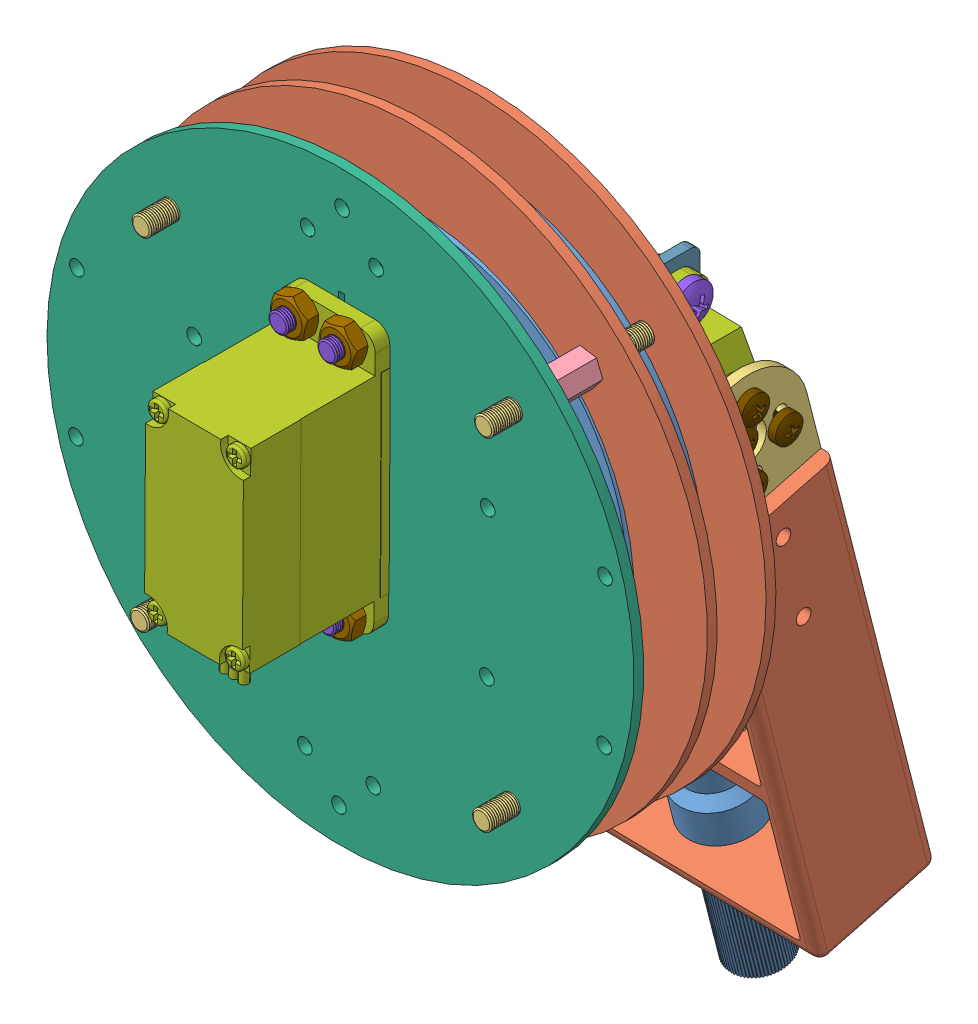
SolidWorks assembly 二自由度云台, configuration 默认. Lengths in mm.
55 component instances, 21 part files, 7 mates.
Components (placement in the parent):
- ______-1: ______ [默认] at (-82.3589 -57.7244 90.6612) x (1 0 0) z (0 -1 0) size (95 10 95)
- ____-1: ____ [默认] at (-82.3589 -57.7244 78.6612) x (0 0 1) z (-0.711112 -0.703078 0) size (2 120 120)
- ____-2: ____ [默认] at (-82.3589 -57.7244 92.6612) x (0 0 -1) z (0.711112 0.703078 0) size (2 120 120)
- cross recessed pan head screws gb_GB_CROSS_SCREWS_TYPE1 M4X35-35  H type-S-1: cross recessed pan head screws gb_GB_CROSS_SCREWS_TYPE1 M4X35-35  H type-S [默认] at (-47.5565 -92.9245 75.5612) x (0 0 1) z (-1 0 0) size (38.1 8.13 8.3)
- cross recessed pan head screws gb_GB_CROSS_SCREWS_TYPE1 M4X35-35  H type-S-2: cross recessed pan head screws gb_GB_CROSS_SCREWS_TYPE1 M4X35-35  H type-S [默认] at (-117.559 -92.5268 75.5612) x (0 0 1) z (-0.986603 0.163137 0) size (38.1 8.13 8.3)
- cross recessed pan head screws gb_GB_CROSS_SCREWS_TYPE1 M4X35-35  H type-S-3: cross recessed pan head screws gb_GB_CROSS_SCREWS_TYPE1 M4X35-35  H type-S [默认] at (-117.1613 -22.5244 75.5612) x (0 0 1) z (0.908259 -0.418408 0) size (38.1 8.13 8.3)
- cross recessed pan head screws gb_GB_CROSS_SCREWS_TYPE1 M4X35-35  H type-S-4: cross recessed pan head screws gb_GB_CROSS_SCREWS_TYPE1 M4X35-35  H type-S [默认] at (-47.1589 -22.922 75.5612) x (0 0 1) z (-1 0 0) size (38.1 8.13 8.3)
- M4X13________-1: M4X13________ [默认] at (-120.1099 -20.7062 92.6612) x (0.880142 0.47471 0) z (0 0 1) size (6.93 6 13)
- M4X13________-2: M4X13________ [默认] at (-43.7311 -23.4224 92.6612) x (-0.619848 -0.784722 0) z (0 0 1) size (6.93 6 13)
- M4X13________-3: M4X13________ [默认] at (-50.9498 -93.6216 92.6612) x (0.315486 0.94893 0) z (0 0 1) size (6.93 6 13)
- M4X13________-4: M4X13________ [默认] at (-119.242 -89.499 92.6612) x (0.999868 -0.016255 0) z (0 0 1) size (6.93 6 13)
- 001______+____Z-1: 001______+____Z [默认] at (-140.6801 -103.9673 61.1412) size (20.06 19.66 8.9)
- 004 ________-1: 004 ________ [默认] at (-77.1222 -62.0034 226.6612) x (0.999983 -0.005885 0) z (0 0 -1) size (120 120 45.5)
  - ________-1: ________ [默认] at (-6.9598 -21.9991 119) size (120 120 2)
  - ________-1-1: ________-1 [默认] at (4.7275 -13.9483 109) x (0 0 1) z (-1 0 0) size (45.5 56 20)
  - cross recessed pan head screws gb_GB_CROSS_SCREWS_TYPE1 M4X10-10  H type-S-1: cross recessed pan head screws gb_GB_CROSS_SCREWS_TYPE1 M4X10-10  H type-S [默认] at (-10.2725 10.0517 124.1) x (0 0 -1) z (1 0 0) size (13.1 8.13 8.3)
  - cross recessed pan head screws gb_GB_CROSS_SCREWS_TYPE1 M4X10-10  H type-S-2: cross recessed pan head screws gb_GB_CROSS_SCREWS_TYPE1 M4X10-10  H type-S [默认] at (-0.2725 10.0517 124.1) x (0 0 -1) z (-0.157245 -0.98756 0) size (13.1 8.13 8.3)
  - cross recessed pan head screws gb_GB_CROSS_SCREWS_TYPE1 M4X10-10  H type-S-3: cross recessed pan head screws gb_GB_CROSS_SCREWS_TYPE1 M4X10-10  H type-S [默认] at (-10.2725 -38.2483 124.1) x (0 0 -1) z (0.153559 0.988139 0) size (13.1 8.13 8.3)
  - cross recessed pan head screws gb_GB_CROSS_SCREWS_TYPE1 M4X10-10  H type-S-4: cross recessed pan head screws gb_GB_CROSS_SCREWS_TYPE1 M4X10-10  H type-S [默认] at (-0.2725 -38.2483 124.1) x (0 0 -1) z (0.042331 0.999104 0) size (13.1 8.13 8.3)
  - hex nuts, style 1-grades ab gb_GB_FASTENER_NUT_SNAB1 M4-S-1: hex nuts, style 1-grades ab gb_GB_FASTENER_NUT_SNAB1 M4-S [默认] at (-0.2725 10.0517 112.8) x (0.195898 -0.980624 0) z (0 0 -1) size (8.08 7 3.2)
  - hex nuts, style 1-grades ab gb_GB_FASTENER_NUT_SNAB1 M4-S-2: hex nuts, style 1-grades ab gb_GB_FASTENER_NUT_SNAB1 M4-S [默认] at (-10.2725 10.0517 112.8) x (0.923728 0.383049 0) z (0 0 -1) size (8.08 7 3.2)
  - hex nuts, style 1-grades ab gb_GB_FASTENER_NUT_SNAB1 M4-S-3: hex nuts, style 1-grades ab gb_GB_FASTENER_NUT_SNAB1 M4-S [默认] at (-0.2725 -38.2483 112.8) x (-0.289317 0.957233 0) z (0 0 -1) size (8.08 7 3.2)
  - hex nuts, style 1-grades ab gb_GB_FASTENER_NUT_SNAB1 M4-S-4: hex nuts, style 1-grades ab gb_GB_FASTENER_NUT_SNAB1 M4-S [默认] at (-10.2725 -38.2483 112.8) x (0.195898 -0.980624 0) z (0 0 -1) size (8.08 7 3.2)
- 装配体2^二自由度云台-1: 装配体2^二自由度云台 [默认] at (-165.8157 -113.8499 0) x (-0.999814 0.019284 0) z (0 0 1) size (82.4 80 45.14)
  - ________-2-1: ________-2 [默认] at (-64.3589 -68.5794 64.7929) x (0 -0.998863 -0.047683) z (0 -0.047683 0.998863) size (10 4 10)
  - cross recessed pan head screws gb_GB_CROSS_SCREWS_TYPE1 M3X8-8  H type-S-1: cross recessed pan head screws gb_GB_CROSS_SCREWS_TYPE1 M3X8-8  H type-S [默认] at (-61.9589 -68.5794 64.7929) x (-1 0 0) z (0 -0.323721 0.946153) size (10.4 5.69 5.85)
  - hex nuts, style 1-grades ab gb_GB_FASTENER_NUT_SNAB1 M3-S-1: hex nuts, style 1-grades ab gb_GB_FASTENER_NUT_SNAB1 M3-S [默认] at (-99.3589 -82.0794 69.6612) x (0 -0.251604 0.96783) z (-1 0 0) size (6.35 5.5 2.4)
  - ________-1-1: ________-1 [默认] at (-94.3589 -58.0794 54.6612) x (-1 0 0) z (0 0 1) size (45.5 56 20)
  - cross recessed pan head screws gb_GB_CROSS_SCREWS_TYPE1 M4X10-10  H type-S-1: cross recessed pan head screws gb_GB_CROSS_SCREWS_TYPE1 M4X10-10  H type-S [默认] at (-107.4589 -82.0794 69.6612) x (1 0 0) z (0 0.191059 0.981579) size (13.1 8.13 8.3)
  - cross recessed pan head screws gb_GB_CROSS_SCREWS_TYPE1 M4X10-10  H type-S-2: cross recessed pan head screws gb_GB_CROSS_SCREWS_TYPE1 M4X10-10  H type-S [默认] at (-107.4589 -82.0794 59.6612) x (1 0 0) z (0 0.369456 -0.929248) size (13.1 8.13 8.3)
  - hex nuts, style 1-grades ab gb_GB_FASTENER_NUT_SNAB1 M4-S-1: hex nuts, style 1-grades ab gb_GB_FASTENER_NUT_SNAB1 M4-S [默认] at (-96.1589 -34.0794 59.6612) x (0 0.334532 0.942384) z (1 0 0) size (8.08 7 3.2)
  - hex nuts, style 1-grades ab gb_GB_FASTENER_NUT_SNAB1 M4-S-2: hex nuts, style 1-grades ab gb_GB_FASTENER_NUT_SNAB1 M4-S [默认] at (-96.1589 -34.0794 69.6612) x (0 0.736012 0.676969) z (1 0 0) size (8.08 7 3.2)
  - hex nuts, style 1-grades ab gb_GB_FASTENER_NUT_SNAB1 M4-S-3: hex nuts, style 1-grades ab gb_GB_FASTENER_NUT_SNAB1 M4-S [默认] at (-96.1589 -82.0794 59.6612) x (0 0.574695 0.818367) z (1 0 0) size (8.08 7 3.2)
  - __________-1: __________ [默认] at (-120.3589 -68.0794 64.6612) x (0 -0.999968 -0.007977) z (0 -0.007977 0.999968) size (20 4.5 20)
  - JXS006-1: JXS006 [默认] at (-101.3589 -28.5794 76.6612) x (0 -1 0) z (0 0 -1) size (59 37 25)
  - cross recessed pan head screws gb_GB_CROSS_SCREWS_TYPE1 M4X10-10  H type-S-3: cross recessed pan head screws gb_GB_CROSS_SCREWS_TYPE1 M4X10-10  H type-S [默认] at (-107.4589 -34.0794 59.6612) x (1 0 0) z (0 0.250072 -0.968227) size (13.1 8.13 8.3)
  - cross recessed pan head screws gb_GB_CROSS_SCREWS_TYPE1 M4X10-10  H type-S-4: cross recessed pan head screws gb_GB_CROSS_SCREWS_TYPE1 M4X10-10  H type-S [默认] at (-107.4589 -34.0794 69.6612) x (1 0 0) z (0 0.369456 -0.929248) size (13.1 8.13 8.3)
  - ________M3_GB_FASTENER_NUT_SNAB1 M3-S-1: ________M3_GB_FASTENER_NUT_SNAB1 M3-S [默认] at (-72.7589 -68.5794 64.7929) x (0 0 1) z (-1 0 0) size (6.35 5.5 2.4)
  - cross recessed pan head screws gb_GB_CROSS_SCREWS_TYPE1 M4X20-20  H type-S-1: cross recessed pan head screws gb_GB_CROSS_SCREWS_TYPE1 M4X20-20  H type-S [默认] at (-57.2566 -32.6221 75.5612) x (0 0 1) z (0.000967 1 0) size (23.1 8.13 8.3)
  - cross recessed pan head screws gb_GB_CROSS_SCREWS_TYPE1 M4X20-20  H type-S-2: cross recessed pan head screws gb_GB_CROSS_SCREWS_TYPE1 M4X20-20  H type-S [默认] at (-107.4612 -32.6221 75.5612) x (0 0 1) z (-0.935907 -0.352246 0) size (23.1 8.13 8.3)
  - cross recessed pan head screws gb_GB_CROSS_SCREWS_TYPE1 M4X20-20  H type-S-3: cross recessed pan head screws gb_GB_CROSS_SCREWS_TYPE1 M4X20-20  H type-S [默认] at (-57.2566 -82.8267 75.7037) x (0 0 1) z (0.999852 -0.017213 0) size (23.1 8.13 8.3)
  - cross recessed pan head screws gb_GB_CROSS_SCREWS_TYPE1 M4X20-20  H type-S-4: cross recessed pan head screws gb_GB_CROSS_SCREWS_TYPE1 M4X20-20  H type-S [默认] at (-107.4612 -82.8267 75.5612) x (0 0 1) z (-1 0 0) size (23.1 8.13 8.3)
  - hex nuts, style 1-grades ab gb_GB_FASTENER_NUT_SNAB1 M4-S-4: hex nuts, style 1-grades ab gb_GB_FASTENER_NUT_SNAB1 M4-S [默认] at (-107.4612 -32.6221 95.8612) size (8.08 7 3.2)
  - hex nuts, style 1-grades ab gb_GB_FASTENER_NUT_SNAB1 M4-S-5: hex nuts, style 1-grades ab gb_GB_FASTENER_NUT_SNAB1 M4-S [默认] at (-57.2566 -32.6221 95.8612) size (8.08 7 3.2)
  - hex nuts, style 1-grades ab gb_GB_FASTENER_NUT_SNAB1 M4-S-6: hex nuts, style 1-grades ab gb_GB_FASTENER_NUT_SNAB1 M4-S [默认] at (-57.2566 -82.8267 95.8612) size (8.08 7 3.2)
  - hex nuts, style 1-grades ab gb_GB_FASTENER_NUT_SNAB1 M4-S-7: hex nuts, style 1-grades ab gb_GB_FASTENER_NUT_SNAB1 M4-S [默认] at (-107.4612 -82.8267 95.8612) size (8.08 7 3.2)
  - ______-0-1: ______-0 [默认] at (-147.1015 -98.2937 78.6612) size (80 80 2)
  - ____M3X6_GB_CROSS_SCREWS_TYPE1 M3X6-6  H type-S-1: ____M3X6_GB_CROSS_SCREWS_TYPE1 M3X6-6  H type-S [默认] at (-124.7589 -61.0796 64.717) x (1 0 0) z (0 -0.924225 0.381849) size (8.4 5.69 5.85)
  - ____M3X6_GB_CROSS_SCREWS_TYPE1 M3X6-6  H type-S-2: ____M3X6_GB_CROSS_SCREWS_TYPE1 M3X6-6  H type-S [默认] at (-122.7589 -67.9806 64.8167) x (1 0 0) z (0 -0.924225 0.381849) size (8.4 5.69 5.85)
  - ____M3X6_GB_CROSS_SCREWS_TYPE1 M3X6-6  H type-S-3: ____M3X6_GB_CROSS_SCREWS_TYPE1 M3X6-6  H type-S [默认] at (-124.7589 -68.0236 57.6614) x (1 0 0) z (0 -0.990334 0.138703) size (8.4 5.69 5.85)
  - ____M3X6_GB_CROSS_SCREWS_TYPE1 M3X6-6  H type-S-4: ____M3X6_GB_CROSS_SCREWS_TYPE1 M3X6-6  H type-S [默认] at (-124.7589 -75.0792 64.6053) x (1 0 0) z (0 -0.924225 0.381849) size (8.4 5.69 5.85)
  - ____M3X6_GB_CROSS_SCREWS_TYPE1 M3X6-6  H type-S-5: ____M3X6_GB_CROSS_SCREWS_TYPE1 M3X6-6  H type-S [默认] at (-124.7589 -68.1353 71.661) x (1 0 0) z (0 -0.924225 0.381849) size (8.4 5.69 5.85)
- 喷头-1: 喷头 [默认] at (-71.3248 -107.9164 48.3788) x (0.994897 0.007958 -0.100579) z (-0.099161 0.261081 -0.96021) size (15 63 15)
- 喷头固定-1: 喷头固定 [默认] at (-42.327 -56.4527 49.4679) x (-0.005024 -0.260489 0.965464) z (0.018618 0.965284 0.260538) size (25 62 86.5)
- JXS005-1: JXS005 [默认] at (-98.0149 -91.5903 39.6977) x (0.999814 -0.019284 0) z (0.018618 0.965284 0.260538) size (56 25 64)
Mates (geometry in assembly coordinates):
- 同心1: concentric aligned: cylinder of 装配体2^二自由度云台-1/________-2-1 through (-100.1463 -46.5243 64.7929) axis (-0.999814 0.019284 0) radius 4; cylinder of JXS005-1 through (-98.1466 -46.5629 64.7929) axis (-0.999814 0.019284 0) radius 4
- 重合1: coincident anti-aligned: plane of 装配体2^二自由度云台-1/JXS006-1 through (-96.9184 -86.594 76.6612) normal (-0.999814 0.019284 0); plane of JXS005-1 through (-97.0151 -91.6096 39.6977) normal (0.999814 -0.019284 0)
- 同心2: concentric aligned: cylinder of 喷头固定-1 through (-98.4911 -64.4207 59.9729) axis (-0.999814 0.019284 0) radius 1.5; cylinder of JXS005-1 through (-98.4911 -64.4207 59.9729) axis (-0.999814 0.019284 0) radius 1.5
- 同心3: concentric aligned: cylinder of 喷头固定-1 through (-98.8076 -80.8305 55.5438) axis (-0.999814 0.019284 0) radius 1.5; cylinder of JXS005-1 through (-98.8076 -80.8305 55.5438) axis (-0.999814 0.019284 0) radius 1.5
- 重合2: coincident anti-aligned: plane of 喷头固定-1 through (-98.3166 -55.3728 49.4679) normal (0.999814 -0.019284 0); plane of JXS005-1 through (-99.0147 -91.571 39.6977) normal (-0.999814 0.019284 0)
- 同心4: concentric anti-aligned: cylinder of 喷头-1 through (-72.4977 -168.7293 31.9649) axis (0.018618 0.965284 0.260538) radius 7.5; cylinder of 喷头固定-1 through (-71.8088 -133.0131 41.605) axis (-0.018618 -0.965284 -0.260538) radius 4.65
- 重合3: coincident aligned: plane of 喷头-1 through (-71.3248 -107.9164 48.3788) normal (0.018618 0.965284 0.260538); plane of 喷头固定-1 through (-99.2568 -104.1204 36.3105) normal (0.018618 0.965284 0.260538)
